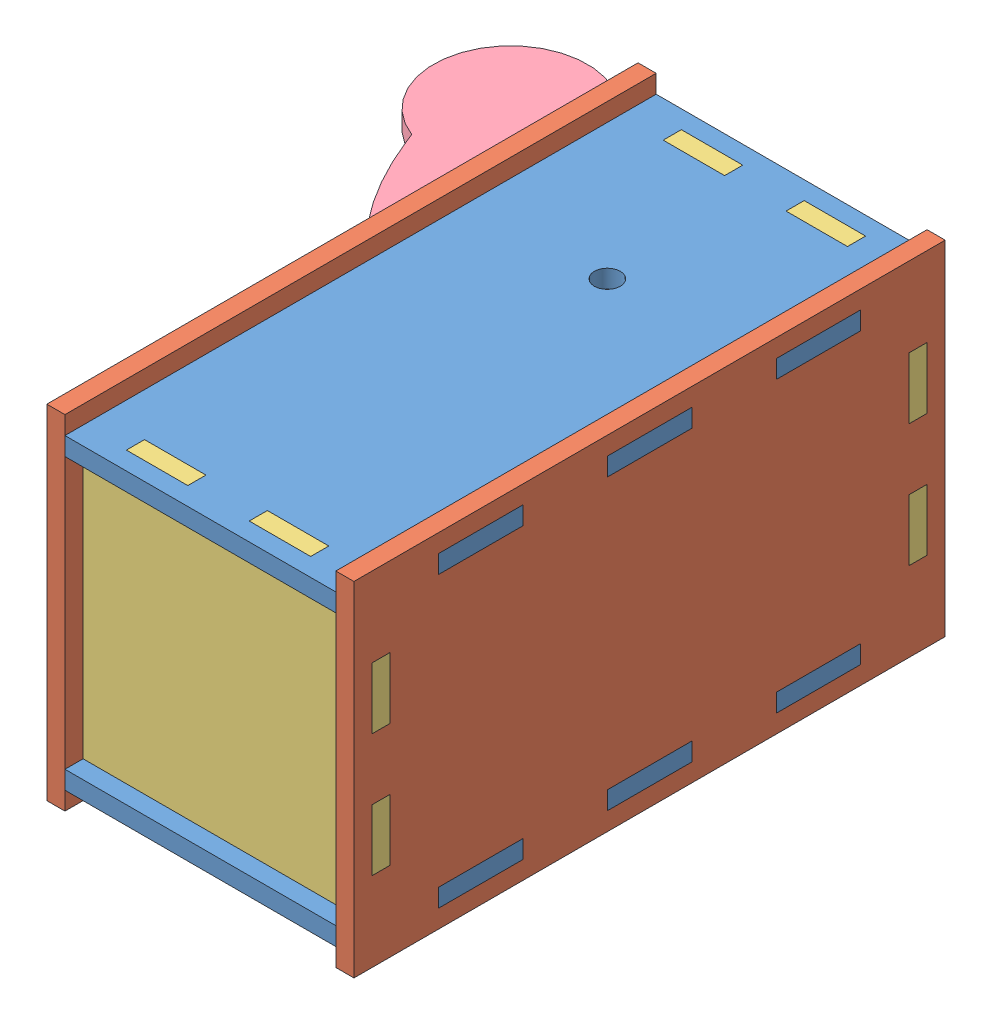
SolidWorks assembly little_box_asm, configuration Default. Lengths in mm.
Overall size (93.82 56.8 121.46).
7 component instances, 4 part files, 18 mates.
Components (placement in the parent):
- little_box_front_back-1: little_box_front_back [Default] at (-21.3595 49.4931 106.6407) size (50.8 3 97.79)
- little_box_front_back-2: little_box_front_back [Default] at (29.4405 100.2931 106.6407) x (-1 0 0) z (0 0 1) size (50.8 3 97.79)
- little_box_sides-1: little_box_sides [outside] at (-21.3595 103.2931 106.6407) x (0 -1 0) z (0 0 1) size (56.8 3 97.79)
- little_box_sides-2: little_box_sides [Default] at (29.4405 103.2931 8.8507) x (0 -1 0) z (0 0 -1) size (56.8 3 97.79)
- little_box_top_bottom-1: little_box_top_bottom [Default] at (29.4405 100.2931 103.6407) x (0 -1 0) z (1 0 0) size (50.8 3 50.8)
- little_box_top_bottom-2: little_box_top_bottom [top] at (29.4405 100.2931 14.8507) x (0 -1 0) z (1 0 0) size (50.8 3 50.8)
- small_box_lever-1: small_box_lever [Default] at (-26.8029 77.4331 37.1282) x (-0.999342 0 0.036267) z (0.036267 0 0.999342) size (73.46 3 65.51)
Mates (geometry in assembly coordinates):
- Coincident3: coincident anti-aligned: plane of little_box_sides-2 through (29.4405 69.8131 100.6407) normal (0 0 1); plane of little_box_top_bottom-1 through (29.4405 100.2931 100.6407) normal (0 0 -1)
- Coincident4: coincident anti-aligned: plane of little_box_sides-2 through (29.4405 69.8131 103.6407) normal (0 -1 0); plane of little_box_top_bottom-1 through (29.4405 69.8131 103.6407) normal (0 1 0)
- Coincident5: coincident anti-aligned: plane of little_box_sides-1 through (-18.3595 103.2931 106.6407) normal (1 0 0); plane of little_box_top_bottom-1 through (-18.3595 100.2931 103.6407) normal (-1 0 0)
- Coincident6: coincident anti-aligned: plane of little_box_sides-1 through (-21.3595 90.1331 100.6407) normal (0 0 1); plane of little_box_top_bottom-1 through (29.4405 100.2931 100.6407) normal (0 0 -1)
- Coincident8: coincident anti-aligned: plane of little_box_sides-1 through (-21.3595 79.9731 103.6407) normal (0 1 0); plane of little_box_top_bottom-1 through (29.4405 79.9731 103.6407) normal (0 -1 0)
- Coincident9: coincident anti-aligned: plane of little_box_front_back-2 through (29.4405 97.2931 106.6407) normal (0 -1 0); plane of little_box_top_bottom-1 through (29.4405 97.2931 103.6407) normal (0 1 0)
- Coincident10: coincident anti-aligned: plane of little_box_front_back-2 through (19.2805 100.2931 100.6407) normal (0 0 1); plane of little_box_top_bottom-1 through (29.4405 100.2931 100.6407) normal (0 0 -1)
- Coincident12: coincident anti-aligned: plane of little_box_front_back-2 through (-11.1995 100.2931 103.6407) normal (1 0 0); plane of little_box_top_bottom-1 through (-11.1995 100.2931 103.6407) normal (-1 0 0)
- Parallel2: parallel anti-aligned: plane of little_box_sides-2 through (29.4405 90.1331 103.6407) normal (0 -1 0); plane of little_box_top_bottom-1 through (29.4405 90.1331 103.6407) normal (0 1 0)
- Coincident14: coincident anti-aligned: plane of little_box_sides-2 through (29.4405 69.8131 103.6407) normal (0 -1 0); plane of little_box_top_bottom-1 through (29.4405 69.8131 103.6407) normal (0 1 0)
- Coincident15: coincident anti-aligned: plane of little_box_sides-2 through (26.4405 103.2931 8.8507) normal (-1 0 0); plane of little_box_top_bottom-1 through (26.4405 100.2931 103.6407) normal (1 0 0)
- Coincident16: coincident anti-aligned: plane of little_box_front_back-1 through (-21.3595 52.4931 106.6407) normal (0 1 0); plane of little_box_top_bottom-1 through (29.4405 52.4931 103.6407) normal (0 -1 0)
- Coincident17: coincident anti-aligned: plane of little_box_front_back-1 through (9.1205 49.4931 100.6407) normal (0 0 1); plane of little_box_top_bottom-1 through (29.4405 100.2931 100.6407) normal (0 0 -1)
- Coincident18: coincident anti-aligned: plane of little_box_front_back-1 through (19.2805 49.4931 103.6407) normal (-1 0 0); plane of little_box_top_bottom-1 through (19.2805 100.2931 103.6407) normal (1 0 0)
- Coincident19: coincident anti-aligned: plane of little_box_sides-1 through (-21.3595 69.8131 14.8507) normal (0 0 -1); plane of little_box_top_bottom-2 through (29.4405 100.2931 14.8507) normal (0 0 1)
- Coincident20: coincident anti-aligned: plane of little_box_sides-1 through (-21.3595 90.1331 11.8507) normal (0 -1 0); plane of little_box_top_bottom-2 through (29.4405 90.1331 14.8507) normal (0 1 0)
- Coincident21: coincident anti-aligned: plane of little_box_sides-2 through (26.4405 103.2931 8.8507) normal (-1 0 0); plane of little_box_top_bottom-2 through (26.4405 100.2931 14.8507) normal (1 0 0)
- Coincident25: coincident anti-aligned: plane of little_box_sides-1 through (-21.3595 77.4331 21.5507) normal (0 -1 0); plane of small_box_lever-1 through (-24.5371 77.4331 27.3653) normal (0 1 0)
